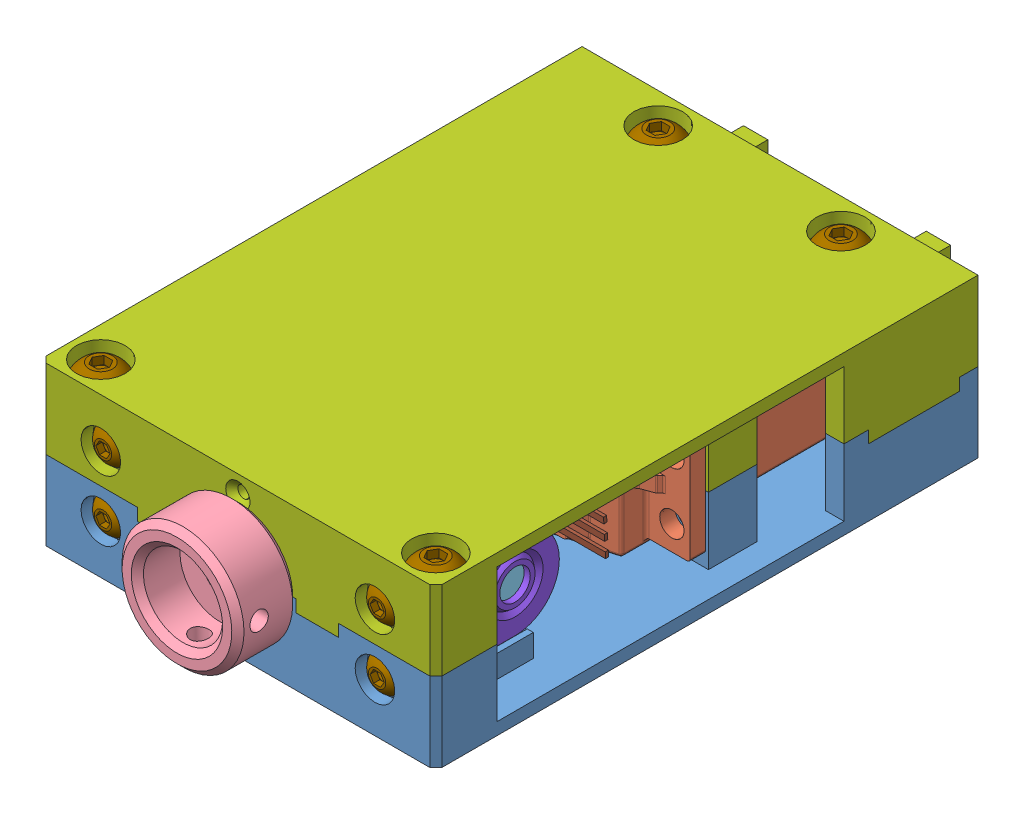
SolidWorks assembly slave, configuration Default. Lengths in mm.
Overall size (65 27.36 110).
22 component instances, 11 part files, 40 mates.
Components (placement in the parent):
- chassi_slave2_inf-1: chassi_slave2_inf [Default] at (0 -0.5 -40) size (65 13 100)
- FUTABA_S3305-1: FUTABA_S3305 [Default] at (0 12.5 -68.5) x (1 0 0) z (0 -1 0) size (55.5 44.6 20)
  - corpo_-1: corpo_ [Default] at origin size (55.5 42.5 20)
  - tampa_-1: tampa_ [Default] at (0 -2.5 0) x (-1 0 0) z (0 -1 0) size (43 20 2.1)
- apoio_acopolamento2_-1: apoio_acopolamento2_ [Default] at (0 12.5 -2) x (0.031894 -0.999491 0) z (-0.999491 -0.031894 0) size (20 17 20)
- eixo_polia-1: eixo_polia [Default] at (0 12.5 -15) x (0 0.053947 -0.998544) z (1 0 0) size (6 6 49)
- Straight Miter Gear_ISO-3: Straight Miter Gear_ISO [ISO - Straight miter gear 0.5M20T 20PA 4FW ---20O75H3MD4.0N] at (-9.5 12.5 -25.1624) x (0 0 1) z (-0.976532 0.215374 0) size (3.65 10.67 10.67)
- Straight Miter Gear_ISO-4: Straight Miter Gear_ISO [ISO - Straight miter gear 0.5M40T 20PA 4FW ---40O75H3MD4.0N] at (-15.9071 12.5 -15) x (1 0 0) z (0 -0.912085 0.410001) size (3.83 20.7 20.7)
- chassi_slave2_sup-1: chassi_slave2_sup [Default] at (0 25.5 -40) x (-1 0 0) z (0 0 1) size (65 15 100)
- Chumaceira-1: Chumaceira [Default] at (22.5 12.5 -5) x (0 -1 0) z (0 0 -1) size (16 8.9 18)
- Chumaceira-2: Chumaceira [Default] at (-22.5 12.5 -5) x (0 -1 0) z (0 0 -1) size (16 8.9 18)
- Socket Button Head Screw_ISO-6: Socket Button Head Screw_ISO [ISO 7380 - M4 x 16 --- 16N] at (-27.5 25.1 0) x (0 -1 0) z (0 0 1) size (18.2 7.6 7.6)
- Socket Button Head Screw_ISO-7: Socket Button Head Screw_ISO [ISO 7380 - M4 x 16 --- 16N] at (27.5 25.1 0) x (0 -1 0) z (0 0 1) size (18.2 7.6 7.6)
- Socket Button Head Screw_ISO-10: Socket Button Head Screw_ISO [ISO 7380 - M3 x 8 --- 8N] at (-22.5 7.5 4.65) x (0 0 -1) z (0 -1 0) size (9.65 5.7 5.7)
- Socket Button Head Screw_ISO-11: Socket Button Head Screw_ISO [ISO 7380 - M3 x 12 --- 12N] at (-22.5 17.5 4.65) x (0 0 -1) z (0 -1 0) size (13.65 5.7 5.7)
- Socket Button Head Screw_ISO-12: Socket Button Head Screw_ISO [ISO 7380 - M3 x 8 --- 8N] at (22.5 7.5 4.65) x (0 0 -1) z (0 -1 0) size (9.65 5.7 5.7)
- Socket Button Head Screw_ISO-13: Socket Button Head Screw_ISO [ISO 7380 - M3 x 8 --- 8N] at (22.5 17.5 4.65) x (0 0 -1) z (0 -1 0) size (9.65 5.7 5.7)
- SUB9_macho-1: SUB9_macho [Default] at (0 6 -84) x (-1 0 0) z (0 0 -1) size (31 12.5 11.5)
- Socket Button Head Screw_ISO-14: Socket Button Head Screw_ISO [ISO 7380 - M4 x 16 --- 16N] at (-15 25.1 -79) x (0 -1 0) z (0 0 1) size (18.2 7.6 7.6)
- Socket Button Head Screw_ISO-15: Socket Button Head Screw_ISO [ISO 7380 - M4 x 16 --- 16N] at (15 25.1 -79) x (0 -1 0) z (0 0 1) size (18.2 7.6 7.6)
- potenciometro-1: potenciometro [Default] at (4.825 13.4228 -24.625) x (0 -0.998505 -0.054669) z (0 0.054669 -0.998505) size (13 29.5 13)
- Socket Button Head Screw_ISO-16: Socket Button Head Screw_ISO [ISO 7380 - M3 x 8 --- 8N] at (-9.5 12.5 -20.3296) x (0 0 -1) z (1 0 0) size (9.65 5.7 5.7)
Mates (geometry in assembly coordinates):
- Concentric5: concentric anti-aligned: cylinder of eixo_polia-1
- Concentric6: concentric aligned: unknown of FUTABA_S3305-1/corpo_-1
- Parallel3: parallel: plane of chassi_slave2_inf-1 through (-32.5 1.5 5) normal (0 1 0)
- Coincident37: coincident anti-aligned: plane of chassi_slave2_inf-1 through (28.25 12.5 -44) normal (0 0 1); plane of FUTABA_S3305-1/corpo_-1 through (27.75 3.5 -44) normal (0 0 -1)
- Concentric16: concentric anti-aligned: cylinder of chassi_slave2_inf-1; cylinder of FUTABA_S3305-1/corpo_-1
- Concentric18: concentric anti-aligned: cylinder of chassi_slave2_inf-1; cylinder of FUTABA_S3305-1/corpo_-1
- Coincident38: coincident anti-aligned: plane of chassi_slave2_inf-1 through (-32.5 12.5 -5) normal (0 1 0); plane of chassi_slave2_sup-1 through (-32.5 12.5 -5) normal (0 -1 0)
- Coincident39: coincident aligned: plane of chassi_slave2_inf-1 through (-32.5 1.5 5) normal (0 0 1); plane of chassi_slave2_sup-1 through (32.5 23.5 5) normal (0 0 1)
- Coincident40: coincident aligned: plane of chassi_slave2_inf-1 through (-32.5 1.5 -85) normal (-1 0 0); plane of chassi_slave2_sup-1 through (-32.5 23.5 -85) normal (-1 0 0)
- Concentric191: concentric aligned: unknown of chassi_slave2_sup-1
- Coincident441: coincident anti-aligned: unknown of chassi_slave2_sup-1
- Concentric201: concentric aligned: unknown of chassi_slave2_sup-1
- Coincident451: coincident anti-aligned: unknown of chassi_slave2_sup-1
- Concentric27: concentric aligned: unknown of Chumaceira-2
- Concentric28: concentric aligned: unknown of Chumaceira-2
- Concentric29: concentric aligned: unknown of Chumaceira-1
- Concentric30: concentric aligned: unknown of Chumaceira-1
- Concentric31: concentric aligned: cylinder of eixo_polia-1; cylinder of Chumaceira-1
- Coincident53: coincident anti-aligned: plane of eixo_polia-1 through (19.5 12.6349 -17.4964) normal (1 0 0); plane of Chumaceira-1 through (19.5 12.5 -15) normal (-1 0 0)
- Concentric262: concentric aligned: cylinder of chassi_slave2_inf-1; cylinder of SUB9_macho-1
- Concentric263: concentric aligned: cylinder of chassi_slave2_inf-1; cylinder of SUB9_macho-1
- Coincident513: coincident anti-aligned: plane of chassi_slave2_inf-1 through (-13 8.5 -84) normal (0 0 -1); plane of SUB9_macho-1 through (15.5 -0.25 -84) normal (0 0 1)
- Coincident514: coincident anti-aligned: plane of chassi_slave2_inf-1 through (32.5 12.5 -5) normal (0 0 -1); plane of Chumaceira-1 through (22.5 11 -5) normal (0 0 1)
- Concentric264: concentric aligned: cylinder of chassi_slave2_inf-1; cylinder of Chumaceira-1
- Concentric265: concentric aligned: cylinder of chassi_slave2_sup-1; cylinder of Chumaceira-1
- Coincident515: coincident anti-aligned: unknown of chassi_slave2_sup-1
- Coincident516: coincident anti-aligned: unknown of chassi_slave2_inf-1
- Coincident517: coincident anti-aligned: plane of chassi_slave2_inf-1 through (-32.5 12.5 -5) normal (0 0 -1); plane of Chumaceira-2 through (-22.5 11 -5) normal (0 0 1)
- Concentric266: concentric aligned: cylinder of chassi_slave2_inf-1; cylinder of Chumaceira-2
- Concentric267: concentric aligned: cylinder of chassi_slave2_sup-1; cylinder of Chumaceira-2
- Coincident518: coincident anti-aligned: unknown of chassi_slave2_sup-1
- Coincident519: coincident anti-aligned: unknown of chassi_slave2_inf-1
- Concentric268: concentric anti-aligned: cylinder of chassi_slave2_inf-1; cylinder of apoio_acopolamento2_-1
- Coincident520: coincident anti-aligned: plane of chassi_slave2_inf-1 through (-32.5 1.5 5) normal (0 0 1); plane of apoio_acopolamento2_-1 through (0.3189 2.5051 5) normal (0 0 -1)
- Concentric269: concentric aligned: unknown of chassi_slave2_sup-1
- Concentric270: concentric aligned: unknown of chassi_slave2_sup-1
- Coincident521: coincident anti-aligned: unknown of chassi_slave2_sup-1
- Coincident522: coincident anti-aligned: unknown of chassi_slave2_sup-1
- Concentric271: concentric anti-aligned: cylinder of ?; cylinder of ?
- Coincident523: coincident anti-aligned: circle of ?; plane of ?
